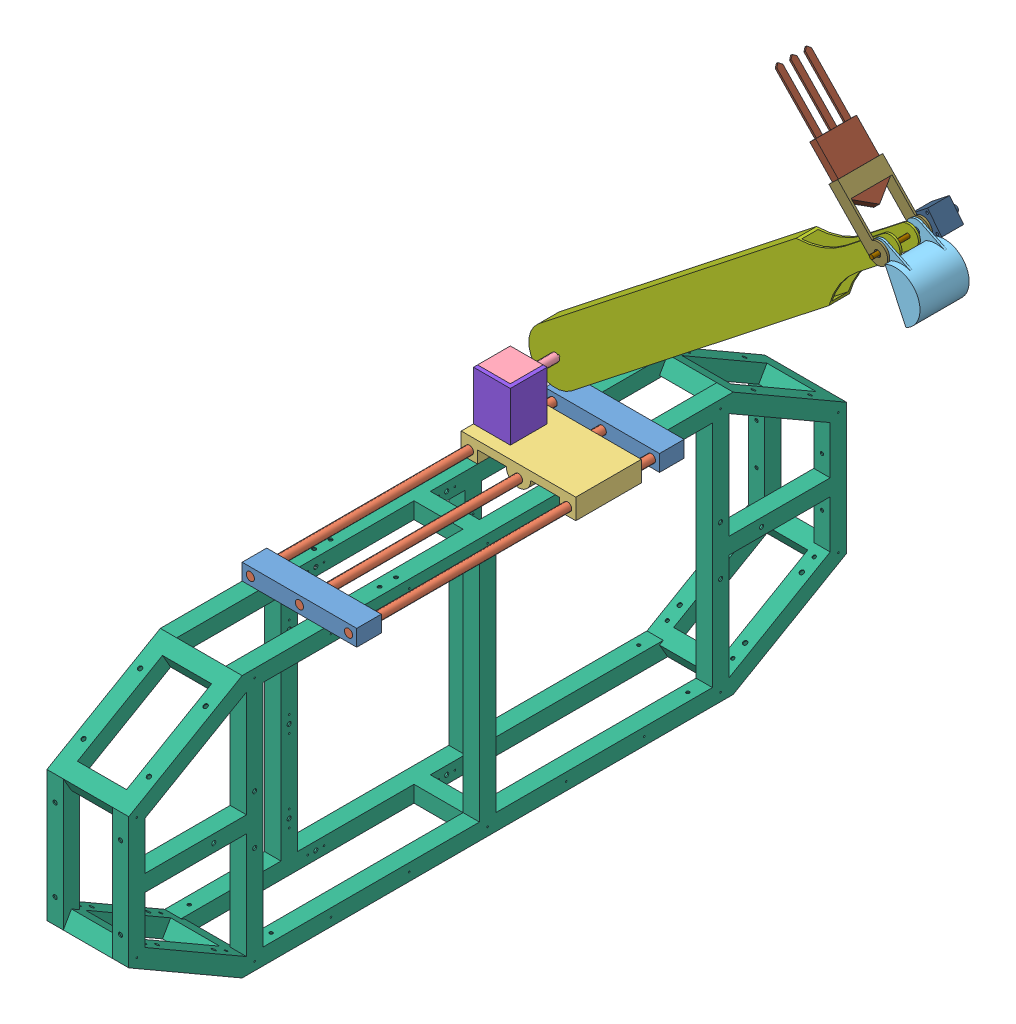
SolidWorks assembly PreliminaryCarriage, configuration Default. Lengths in mm.
Overall size (658.4 1068.06 1113.95).
15 component instances, 12 part files, 39 mates.
Components (placement in the parent):
- PreliminarySupportRailBlonk-1: PreliminarySupportRailBlonk [Default] at origin size (177.8 25.4 38.1)
- PreliminaryCarriageSupportsAndLeadScrew-1: PreliminaryCarriageSupportsAndLeadScrew [Default] at (0 0 508) x (0.522843 -0.852429 0) z (0.852429 0.522843 0) size (12.7 508 12.7)
- PreliminaryCarriageSupportsAndLeadScrew-2: PreliminaryCarriageSupportsAndLeadScrew [Default] at (-76.2 0 508) x (0.392438 -0.919779 0) z (0.919779 0.392438 0) size (12.7 508 12.7)
- PreliminaryCarriageSupportsAndLeadScrew-3: PreliminaryCarriageSupportsAndLeadScrew [Default] at (76.2 0 508) x (-0.610696 -0.791865 0) z (0.791865 -0.610696 0) size (12.7 508 12.7)
- PreliminarySupportRailBlonk-2: PreliminarySupportRailBlonk [Default] at (0 0 469.9) size (177.8 25.4 38.1)
- PreliminaryCarriage-1: PreliminaryCarriage [Default] at (0 6.35 117.2197) size (177.8 31.75 101.6)
- joint1barebonesmotor-1: joint1barebonesmotor [Default] at (-63.5 70.6298 142.6197) x (1 0 0) z (0 1 0) size (50.8 127 50.8)
- PreliminaryExcavator-1: PreliminaryExcavator [ExcavatorForLinearRail] at (470.37 473.6847 31.4947) x (0 0 1) z (0.339753 0.940515 0) size (76.2 96.79 69.76)
- Chassis-20181016-CHA-RevA3-1: Chassis-20181016-CHA-RevA3 [Default] at (25.4 -215.9 254) x (0 0 -1) z (0 1 0) size (1113.95 127 406.4)
- PreliminaryLink1-3: PreliminaryLink1 [Link1Alt] at (-77.6718 88.6354 32.1667) x (0.618486 -0.785796 0) z (0 0 1) size (82.55 717.55 31.75)
- Joint1adapterblock-1: Joint1adapterblock [LinearRailAdapter] at (-63.5 19.05 117.2197) x (0 0 -1) z (1 0 0) size (57.15 76.2 57.15)
- QuarterInchDiameterPinThreeAndAQuarterInches-1: QuarterInchDiameterPinThreeAndAQuarterInches [Default] at (455.4394 479.0782 -12.9553) x (0.271456 0.962451 0) z (0.962451 -0.271456 0) size (6.35 88.9 6.35)
- joint3barebonesmotor-1: joint3barebonesmotor [Default] at (455.4394 479.0782 -42.3803) x (-0.785796 -0.618486 0) z (-0.618486 0.785796 0) size (35.56 70 35.56)
- 5TEMockUp-1: 5TEMockUp [Default] at (404.592 522.6721 31.4947) x (0 0 -1) z (0.719926 0.694051 0) size (63.5 190.36 12.7)
- ProbeBracket-1: ProbeBracket [Default] at (404.592 522.6721 31.4947) x (0 0 -1) z (0.719926 0.694051 0) size (69.85 107.95 31.75)
Mates (geometry in assembly coordinates):
- Concentric1: concentric anti-aligned: cylinder of PreliminarySupportRailBlonk-1 through (-76.2 0 38.1) axis (0 0 -1) radius 6.35; cylinder of PreliminaryCarriageSupportsAndLeadScrew-2 through (-76.2 0 0) axis (0 0 1) radius 6.35
- Concentric2: concentric anti-aligned: cylinder of PreliminarySupportRailBlonk-1 through (0 0 38.1) axis (0 0 -1) radius 6.35; cylinder of PreliminaryCarriageSupportsAndLeadScrew-1 through (0 0 0) axis (0 0 1) radius 6.35
- Concentric3: concentric anti-aligned: cylinder of PreliminarySupportRailBlonk-1 through (76.2 0 38.1) axis (0 0 -1) radius 6.35; cylinder of PreliminaryCarriageSupportsAndLeadScrew-3 through (76.2 0 0) axis (0 0 1) radius 6.35
- Coincident1: coincident aligned: plane of PreliminarySupportRailBlonk-1 through (0 0 0) normal (0 0 -1); plane of PreliminaryCarriageSupportsAndLeadScrew-3 through (76.2 0 0) normal (0 0 -1)
- Coincident2: coincident aligned: plane of PreliminarySupportRailBlonk-1 through (0 0 0) normal (0 0 -1); plane of PreliminaryCarriageSupportsAndLeadScrew-1 through (0 0 0) normal (0 0 -1)
- Coincident3: coincident aligned: plane of PreliminarySupportRailBlonk-1 through (0 0 0) normal (0 0 -1); plane of PreliminaryCarriageSupportsAndLeadScrew-2 through (-76.2 0 0) normal (0 0 -1)
- Concentric4: concentric anti-aligned: cylinder of PreliminaryCarriageSupportsAndLeadScrew-2 through (-76.2 0 0) axis (0 0 1) radius 6.35; cylinder of PreliminarySupportRailBlonk-2 through (-76.2 0 508) axis (0 0 -1) radius 6.35
- Concentric5: concentric anti-aligned: cylinder of PreliminaryCarriageSupportsAndLeadScrew-1 through (0 0 0) axis (0 0 1) radius 6.35; cylinder of PreliminarySupportRailBlonk-2 through (0 0 508) axis (0 0 -1) radius 6.35
- Concentric6: concentric anti-aligned: cylinder of PreliminaryCarriageSupportsAndLeadScrew-3 through (76.2 0 0) axis (0 0 1) radius 6.35; cylinder of PreliminarySupportRailBlonk-2 through (76.2 0 508) axis (0 0 -1) radius 6.35
- Coincident4: coincident aligned: plane of PreliminaryCarriageSupportsAndLeadScrew-1 through (0 0 508) normal (0 0 1); plane of PreliminarySupportRailBlonk-2 through (0 0 508) normal (0 0 1)
- Concentric7: concentric aligned: cylinder of PreliminaryCarriageSupportsAndLeadScrew-1 through (0 0 0) axis (0 0 1) radius 6.35; cylinder of PreliminaryCarriage-1 through (0 0 48.4592) axis (0 0 1) radius 6.35
- Concentric8: concentric aligned: cylinder of PreliminaryCarriageSupportsAndLeadScrew-2 through (-76.2 0 0) axis (0 0 1) radius 6.35; cylinder of PreliminaryCarriage-1 through (-76.2 0 48.4592) axis (0 0 1) radius 6.35
- Concentric9: concentric aligned: cylinder of PreliminaryCarriageSupportsAndLeadScrew-3 through (76.2 0 0) axis (0 0 1) radius 6.35; cylinder of PreliminaryCarriage-1 through (76.2 0 48.4592) axis (0 0 1) radius 6.35
- Width1: width aligned: plane of PreliminaryCarriage-1 through (-88.9 19.05 168.0197) normal (0 0 1); plane of joint1barebonesmotor-1 through (-88.9 19.05 66.4197) normal (0 0 -1); plane of PreliminaryCarriage-1 through (-63.5 70.6298 142.6197) normal (0 0 1); plane of joint1barebonesmotor-1 through (-63.5 70.6298 91.8197) normal (0 0 -1)
- LimitDistance1: limit distance = 301.8803 mm anti-aligned: plane of PreliminaryCarriage-1 through (-88.9 19.05 168.0197) normal (0 0 1); plane of PreliminarySupportRailBlonk-2 through (0 0 469.9) normal (0 0 -1)
- Coincident12: coincident aligned: plane of PreliminaryCarriage-1 through (-88.9 19.05 168.0197) normal (-1 0 0); plane of Chassis-20181016-CHA-RevA3-1 through (-88.9 -34.697 -114.3) normal (-1 0 0)
- Width3: width aligned: plane of Chassis-20181016-CHA-RevA3-1 through (-88.9 -317.5 810.9764) normal (0 0 1); plane of PreliminarySupportRailBlonk-2 through (-88.9 -114.3 -302.9764) normal (0 0 -1); plane of Chassis-20181016-CHA-RevA3-1 through (0 0 508) normal (0 0 1); plane of PreliminarySupportRailBlonk-1 through (0 0 0) normal (0 0 -1)
- Concentric15: concentric anti-aligned: cylinder of PreliminaryExcavator-1 through (455.4394 479.0782 69.05) axis (0 0 -1) radius 3.175; cylinder of PreliminaryLink1-3 through (455.4394 479.0782 6.6395) axis (0 0 1) radius 3.175
- Width4: width anti-aligned: plane of PreliminaryExcavator-1 through (455.4394 479.0782 56.8947) normal (0 0 -1); plane of PreliminaryLink1-3 through (455.4394 479.0782 6.0947) normal (0 0 1); plane of PreliminaryExcavator-1 through (321.5123 402.8264 15.6197) normal (0 0 -1); plane of PreliminaryLink1-3 through (321.5123 402.8264 47.3697) normal (0 0 1)
- Coincident16: coincident aligned: plane of PreliminaryCarriage-1 through (-88.9 19.05 168.0197) normal (-1 0 0); plane of Joint1adapterblock-1 through (-88.9 44.45 142.6197) normal (-1 0 0)
- Parallel1: parallel aligned: plane of PreliminaryCarriage-1 through (-88.9 19.05 168.0197) normal (0 0 1); plane of Joint1adapterblock-1 through (-88.9 95.25 148.9697) normal (0 0 1)
- Coincident18: coincident anti-aligned: plane of PreliminaryCarriage-1 through (0 19.05 117.2197) normal (0 1 0); plane of Joint1adapterblock-1 through (-63.5 19.05 117.2197) normal (0 -1 0)
- Coincident19: coincident anti-aligned: plane of joint1barebonesmotor-1 through (-63.5 70.6298 142.6197) normal (0 0 1); plane of Joint1adapterblock-1 through (-88.9 95.25 142.6197) normal (0 0 -1)
- Coincident20: coincident aligned: plane of joint1barebonesmotor-1 through (-88.9 95.25 91.8197) normal (0 1 0); plane of Joint1adapterblock-1 through (-63.5 95.25 117.2197) normal (0 1 0)
- Coincident21: coincident aligned: plane of joint1barebonesmotor-1 through (-88.9 95.25 91.8197) normal (-1 0 0); plane of Joint1adapterblock-1 through (-88.9 44.45 142.6197) normal (-1 0 0)
- Concentric16: concentric anti-aligned: cylinder of joint1barebonesmotor-1 through (-63.5 70.6298 15.6197) axis (0 0 1) radius 6.35; cylinder of PreliminaryLink1-3 through (-63.5 70.6298 65.3302) axis (0 0 -1) radius 6.35
- Coincident22: coincident aligned: circle of joint1barebonesmotor-1; plane of PreliminaryLink1-3 through (321.5123 402.8264 15.6197) normal (0 0 -1)
- Coincident23: coincident anti-aligned: plane of PreliminarySupportRailBlonk-2 through (-88.9 -12.7 508) normal (0 -1 0); plane of Chassis-20181016-CHA-RevA3-1 through (38.1 -12.7 -127) normal (0 1 0)
- Concentric17: concentric aligned: cylinder of PreliminaryExcavator-1 through (455.4394 479.0782 69.05) axis (0 0 -1) radius 3.175; cylinder of QuarterInchDiameterPinThreeAndAQuarterInches-1 through (455.4394 479.0782 75.9447) axis (0 0 -1) radius 3.175
- Width5: width anti-aligned: plane of PreliminaryLink1-3 through (321.5123 402.8264 47.3697) normal (0 0 1); plane of QuarterInchDiameterPinThreeAndAQuarterInches-1 through (321.5123 402.8264 15.6197) normal (0 0 -1); plane of PreliminaryLink1-3 through (455.4394 479.0782 -12.9553) normal (0 0 -1); plane of QuarterInchDiameterPinThreeAndAQuarterInches-1 through (455.4394 479.0782 75.9447) normal (0 0 1)
- Concentric18: concentric aligned: cylinder of QuarterInchDiameterPinThreeAndAQuarterInches-1 through (455.4394 479.0782 75.9447) axis (0 0 -1) radius 3.175; cylinder of joint3barebonesmotor-1 through (455.4394 479.0782 15.6197) axis (0 0 -1) radius 5
- Coincident24: coincident anti-aligned: plane of PreliminaryLink1-3 through (321.5123 402.8264 15.6197) normal (0 0 -1); plane of joint3barebonesmotor-1 through (455.4394 479.0782 15.6197) normal (0 0 1)
- Parallel2: parallel aligned: plane of PreliminaryLink1-3 through (-58.2446 76.7865 55.9187) normal (-0.785796 -0.618486 0); plane of joint3barebonesmotor-1 through (430.4712 482.053 -8.3803) normal (-0.785796 -0.618486 0)
- LimitAngle1: limit planar angle = 2.474778 rad anti-aligned: plane of PreliminaryLink1-3 through (310.1561 417.2546 32.1667) normal (-0.618486 0.785796 0); plane of Chassis-20181016-CHA-RevA3-1 through (38.1 -12.7 -127) normal (0 1 0)
- Concentric19: concentric anti-aligned: cylinder of QuarterInchDiameterPinThreeAndAQuarterInches-1 through (455.4394 479.0782 75.9447) axis (0 0 -1) radius 3.175; cylinder of ProbeBracket-1 through (455.4394 479.0782 -17.5832) axis (0 0 1) radius 5.0038
- Width6: width anti-aligned: plane of PreliminaryLink1-3 through (321.5123 402.8264 47.3697) normal (0 0 1); plane of ProbeBracket-1 through (321.5123 402.8264 15.6197) normal (0 0 -1); plane of PreliminaryLink1-3 through (391.5346 545.3654 -0.2553) normal (0 0 1); plane of ProbeBracket-1 through (391.5346 545.3654 63.2447) normal (0 0 -1)
- Coincident28: coincident aligned: line of 5TEMockUp-1 through (409.1635 527.0793 -0.2553) axis (-0.719926 -0.694051 0); line of ProbeBracket-1 through (411.4492 529.2829 -0.2553) axis (-0.719926 -0.694051 0)
- Coincident29: coincident aligned: line of 5TEMockUp-1 through (400.0204 518.2648 63.2447) axis (0.719926 0.694051 0); line of ProbeBracket-1 through (409.1635 527.0793 63.2447) axis (0.719926 0.694051 0)
- Coincident30: coincident anti-aligned: plane of 5TEMockUp-1 through (347.1337 573.1232 63.2447) normal (-0.719926 -0.694051 0); plane of ProbeBracket-1 through (382.3915 536.5509 63.2447) normal (0.719926 0.694051 0)
